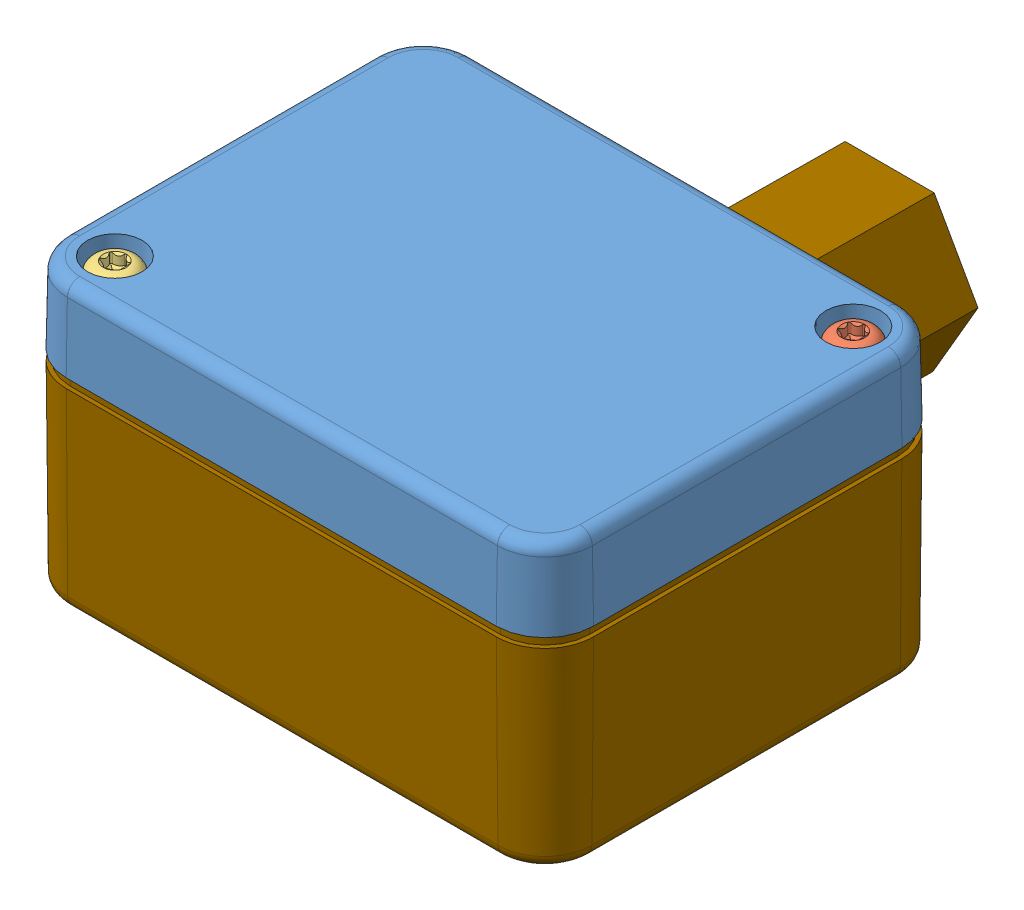
SolidWorks assembly Assem2, configuration Default. Lengths in mm.
Overall size (65.66 34.99 75.31).
12 component instances, 11 part files, 6 mates.
Components (placement in the parent):
- serpac_camera_enclosure-1: serpac_camera_enclosure [Default] at (21.7561 39.3074 52.6491) size (65.66 34.99 75.31)
  - RB32-X04Y REV C(Default)-1: RB32-X04Y REV C(Default) [Default] at origin size (65 10 50)
  - 6023_Pan_Head_screw_torx_head-4-40_Rev_B-1: 6023_Pan_Head_screw_torx_head-4-40_Rev_B [Default] at (26.4999 -17.94 -19) x (1 0 0) z (0 1 0) size (5.56 5.56 27.69)
  - 6023_Pan_Head_screw_torx_head-4-40_Rev_B-1-1: 6023_Pan_Head_screw_torx_head-4-40_Rev_B-1 [Default] at (-26.4999 -17.94 19) x (1 0 0) z (0 1 0) size (5.56 5.56 27.69)
  - 6102_4-40_threaded insert-1: 6102_4-40_threaded insert [Default] at (26.4999 -6.096 -19) x (-0.837169 0 -0.546944) z (-0.546944 0 0.837169) size (5.82 5.08 5.82)
  - 6102_4-40_threaded insert-1-1: 6102_4-40_threaded insert-1 [Default] at (-26.4999 -6.096 19) x (-0.837169 0 -0.546944) z (-0.546944 0 0.837169) size (5.82 5.08 5.82)
  - 6022 #10-16 HL Pan HD-1: 6022 #10-16 HL Pan HD [Default] at (-18.9992 -17.018 0) x (1 0 0) z (0 1 0) size (8.18 8.18 9.67)
  - 6022 #10-16 HL Pan HD-1-1: 6022 #10-16 HL Pan HD-1 [Default] at (18.9992 -17.018 0) x (1 0 0) z (0 1 0) size (8.18 8.18 9.67)
  - 8032 RB32 O ring Rev A-1: 8032 RB32 O ring Rev A [Default] at origin size (62.56 2.03 47.57)
  - Part12-1: Part12 [With Gland] x (-1 0 0) z (0 0 1) size (65.66 26.99 75.31)
- ELP_USB_Camera-1: ELP_USB_Camera [Default] at (21.7561 30.3178 55.1491) x (-1 0 0) z (0 1 0) size (38 38 25.6)
- ELP_Camera_Bracket-1: ELP_Camera_Bracket [Default] at (21.7561 22.3178 52.6491) x (-1 0 0) z (0 0 -1) size (53.96 6.4 38)
Mates (geometry in assembly coordinates):
- Coincident1: coincident anti-aligned: plane of serpac_camera_enclosure-1/RB32-X04Y REV C(Default)-1 through (-4.7438 46.3178 41.8491) normal (0 -1 0); plane of ELP_USB_Camera-1 through (21.7561 46.3178 55.1491) normal (0 1 0)
- Distance2: distance = 1 mm: plane of ELP_USB_Camera-1 through (40.7561 28.7178 36.1491) normal (0 0 -1); line of serpac_camera_enclosure-1/Part12-1 through (28.107 39.3363 35.1491) axis (-1 0 0)
- Coincident10: coincident anti-aligned: plane of ? through (21.7561 39.3074 52.6491) normal (1 0 0); plane of ELP_USB_Camera-1 through (21.7561 30.3178 55.1491) normal (-1 0 0)
- Concentric1: concentric aligned: cylinder of ELP_USB_Camera-1 through (38.7561 28.7168 72.1491) axis (0 1 0) radius 1; cylinder of ELP_Camera_Bracket-1 through (38.7561 -31.4223 72.1491) axis (0 1 0) radius 1
- Coincident11: coincident anti-aligned: plane of ELP_USB_Camera-1 through (21.7561 28.7178 55.1491) normal (0 -1 0); plane of ELP_Camera_Bracket-1 through (21.7561 28.7178 52.6491) normal (0 1 0)
- Concentric2: concentric aligned: cylinder of ELP_USB_Camera-1 through (4.7561 28.7168 38.1491) axis (0 1 0) radius 1; cylinder of ELP_Camera_Bracket-1 through (4.7561 -31.4223 38.1491) axis (0 1 0) radius 1
